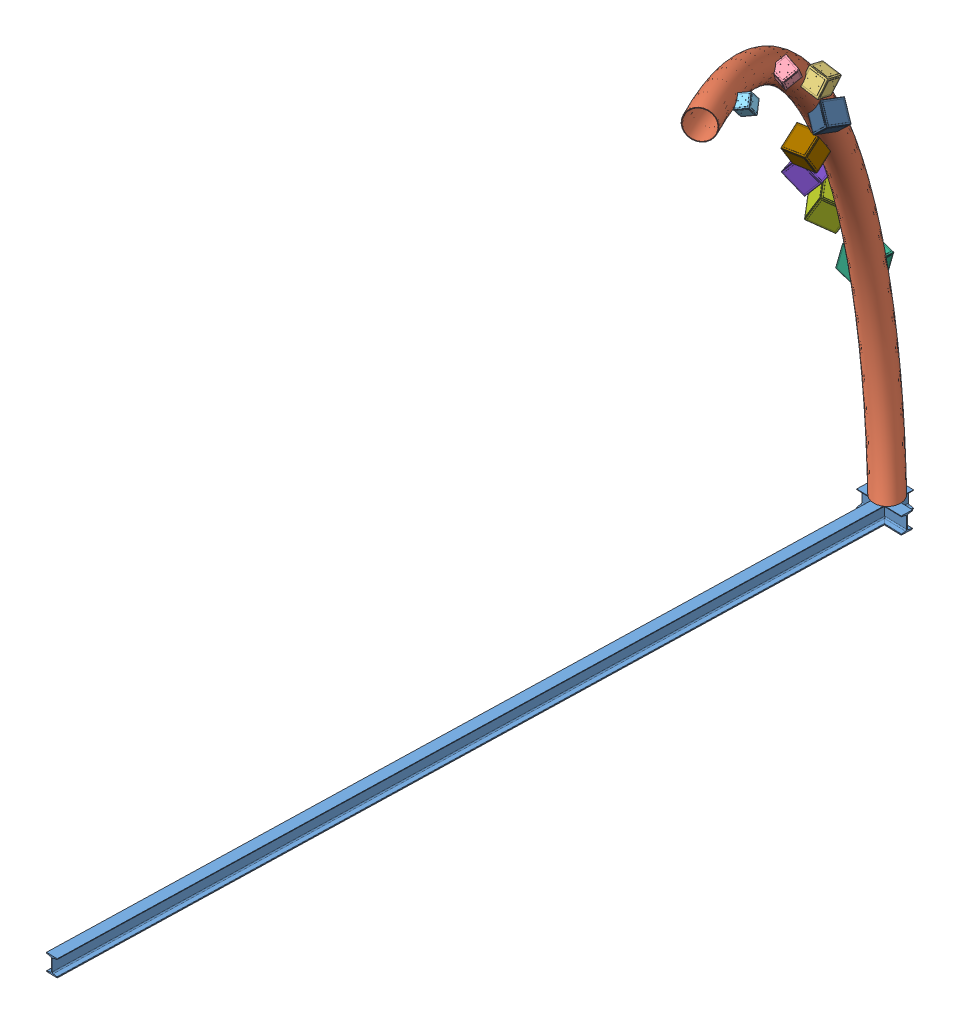
SolidWorks assembly tube4A, configuration Default. Lengths in mm.
Overall size (11936.67 6342.03 7419.9).
11 component instances, 11 part files, 26 mates.
Components (placement in the parent):
- cube_positions-1: cube_positions [Default] at (8904.7669 0 -1666.8962) x (-0.98414 0 0.177396) z (-0.177396 0 -0.98414) size (10173.18 3894.08 5705.72) (hidden)
- ground_anchor^tube4A-1: ground_anchor^tube4A [Default] at (9566.8333 -60.325 -1104.0246) x (-0.999452 0 0.033088) z (0 -1 0) size (470.34 5095.97 101.6) (virtual)
- tubes-1: tubes [tube4A] at (840.8937 1535.1212 -511.9514) x (0.194163 0.849473 0.490608) z (0.490608 -0.517175 0.701309) size (5156.33 178.46 3757.36)
- cube_06-2: cube_06 [Default] at (471.5315 2748.7735 -1138.0748) x (0.201369 0.905147 -0.374379) z (0.964745 -0.249399 -0.084066) size (112.39 112.39 116.4)
- cube_07-2: cube_07 [Default] at (645.566 3070.0096 -753.4371) x (0.234737 0.447214 -0.863075) z (0.927023 -0.370117 0.060349) size (97.16 97.16 101.09)
- cube_08-2: cube_08 [Default] at (942.6163 3319.9065 -214.0269) x (-0.520827 0.525094 -0.673064) z (0.853659 0.322603 -0.408894) size (81.92 81.92 85.85)
- cube_01-2: cube_01 [Default] at (-37.904 1151.3192 -1919.5434) x (-0.033713 0.00175 0.99943) z (-0.959686 0.279148 -0.032861) size (163.19 163.19 163.19)
- cube_02-2: cube_02 [Default] at (-88.0911 1506.3364 -1758.7081) x (0.627621 -0.148413 0.764242) z (-0.63488 0.470576 0.612769) size (158.12 158.12 158.12)
- cube_03-2: cube_03 [Default] at (-39.521 1804.2306 -1588.2847) x (0.643801 0.761931 -0.070581) z (-0.729232 0.638874 0.245073) size (150.61 150.49 150.49)
- cube_04-2: cube_04 [Default] at (125.08 2085.0042 -1403.7965) x (0.992472 0.073499 -0.097969) z (-0.011929 0.85412 0.519939) size (140.33 142.17 140.33)
- cube_05-2: cube_05 [Default] at (346.6784 2408.9309 -1315.8693) x (0.718959 0.693701 0.043313) z (-0.249968 0.199916 0.947391) size (127.64 128.2 127.64)
Mates (geometry in assembly coordinates):
- Lock1: lock: unknown of assembly; unknown of ?
- Coincident1: coincident anti-aligned: plane of ground_anchor^tube4A-1 through (449.1246 0 3216.5534) normal (0 -1 0); plane of assembly through (0 0 0) normal (0 1 0)
- Coincident2: coincident aligned: plane of cube_positions-1 through (290.8601 2818.3314 -1040.6765) normal (-0.964745 0.249399 0.084066); plane of ? through (273.0562 2780.0027 -1131.2857) normal (-0.964745 0.249399 0.084066)
- Coincident3: coincident aligned: plane of cube_positions-1 through (391.4267 2792.3336 -1049.4396) normal (0.169461 0.344252 0.923457); plane of ? through (302.0514 2811.2686 -1040.0973) normal (0.169461 0.344252 0.923457)
- Coincident4: coincident aligned: plane of cube_positions-1 through (352.7707 2662.0943 -1106.6765) normal (-0.201369 -0.905147 0.374379); plane of ? through (279.8176 2716.5511 -1014.2543) normal (-0.201369 -0.905147 0.374379)
- Coincident5: coincident aligned: plane of cube_positions-1 through (529.5721 2928.2446 -651.0495) normal (-0.234737 -0.447214 0.863075); plane of ? through (472.6851 3024.1588 -616.8223) normal (-0.234737 -0.447214 0.863075)
- Coincident6: coincident aligned: plane of cube_positions-1 through (555.7789 3001.2111 -606.1133) normal (0.29245 0.814257 0.501457); plane of ? through (496.1249 3071.64 -685.6843) normal (0.29245 0.814257 0.501457)
- Coincident7: coincident aligned: plane of cube_positions-1 through (529.5721 2928.2446 -651.0495) normal (0.927023 -0.370117 0.060349); plane of ? through (572.7933 3030.8022 -685.9928) normal (0.927023 -0.370117 0.060349)
- Coincident8: coincident aligned: plane of cube_positions-1 through (958.6365 3187.3449 -144.6636) normal (0.520827 -0.525094 0.673064); plane of ? through (896.5032 3255.773 -43.1995) normal (0.520827 -0.525094 0.673064)
- Coincident9: coincident aligned: plane of cube_positions-1 through (958.6365 3187.3449 -144.6636) normal (0.853659 0.322603 -0.408894); plane of ? through (920.9236 3217.9385 -199.2603) normal (0.853659 0.322603 -0.408894)
- Coincident10: coincident aligned: plane of cube_positions-1 through (894.6285 3163.1558 -114.0044) normal (-0.002425 0.78753 0.616271); plane of ? through (859.0501 3202.016 -163.8037) normal (-0.002425 0.78753 0.616271)
- Coincident11: coincident aligned: plane of cube_positions-1 through (327.9374 1299.244 -1832.7332) normal (-0.009503 -0.287348 -0.957779); plane of cube_01-2
- Coincident12: coincident aligned: plane of cube_positions-1 through (327.9374 1299.244 -1832.7332) normal (-0.002851 0.957826 -0.287334); plane of cube_01-2
- Coincident13: coincident aligned: plane of cube_positions-1 through (329.3857 1343.0359 -1686.7676) normal (0.999951 0 -0.009921); plane of cube_01-2
- Coincident14: coincident aligned: plane of cube_positions-1 through (223.4586 1552.0894 -1822.9385) normal (0.48311 -0.393919 -0.781942); plane of cube_02-2
- Coincident15: coincident aligned: plane of cube_positions-1 through (254.2553 1688.8052 -1872.7847) normal (0.207047 0.919145 -0.335118); plane of cube_02-2
- Coincident16: coincident aligned: plane of cube_positions-1 through (349.9978 1552.0894 -1744.7584) normal (0.850727 0 0.525608); plane of cube_02-2
- Coincident17: coincident: plane of cube_positions-1 through (330.0926 1977.2247 -1810.7438) normal (0.835276 -0.271588 -0.478074); plane of cube_03-2
- Coincident18: coincident: plane of cube_positions-1 through (330.0926 1977.2247 -1810.7438) normal (-0.184579 0.680529 -0.709091); plane of cube_03-2
- Coincident19: coincident aligned: plane of cube_positions-1 through (212.2165 2015.5519 -1743.2769) normal (0.517924 0.680529 0.5183); plane of cube_03-2
- Coincident20: coincident: plane of cube_positions-1 through (314.0427 2114.7494 -1584.7954) normal (0.090394 -0.23703 -0.967288); plane of cube_04-2
- Coincident21: coincident: plane of cube_positions-1 through (280.6852 2237.0994 -1617.8941) normal (-0.254513 0.933513 -0.252538); plane of cube_04-2
- Coincident22: coincident aligned: plane of cube_positions-1 through (314.0427 2114.7494 -1584.7954) normal (0.962835 0.269016 0.024057); plane of cube_04-2
- Coincident23: coincident: plane of cube_positions-1 through (232.3027 2359.0281 -1336.4217) normal (0.106497 -0.478574 -0.871565); line of cube_05-2 through (313.6743 2401.8885 -1350.0134) axis (0.046336 -0.873209 0.485139)
- Coincident24: coincident: plane of cube_positions-1 through (298.8916 2496.3444 -1267.9955) normal (-0.735086 0.552362 -0.393121); plane of cube_05-2
- Coincident25: coincident aligned: plane of cube_positions-1 through (385.8246 2431.0207 -1221.5041) normal (0.669557 0.682541 -0.292969); sketch_entity of tubes-1; circle of tubes-1
